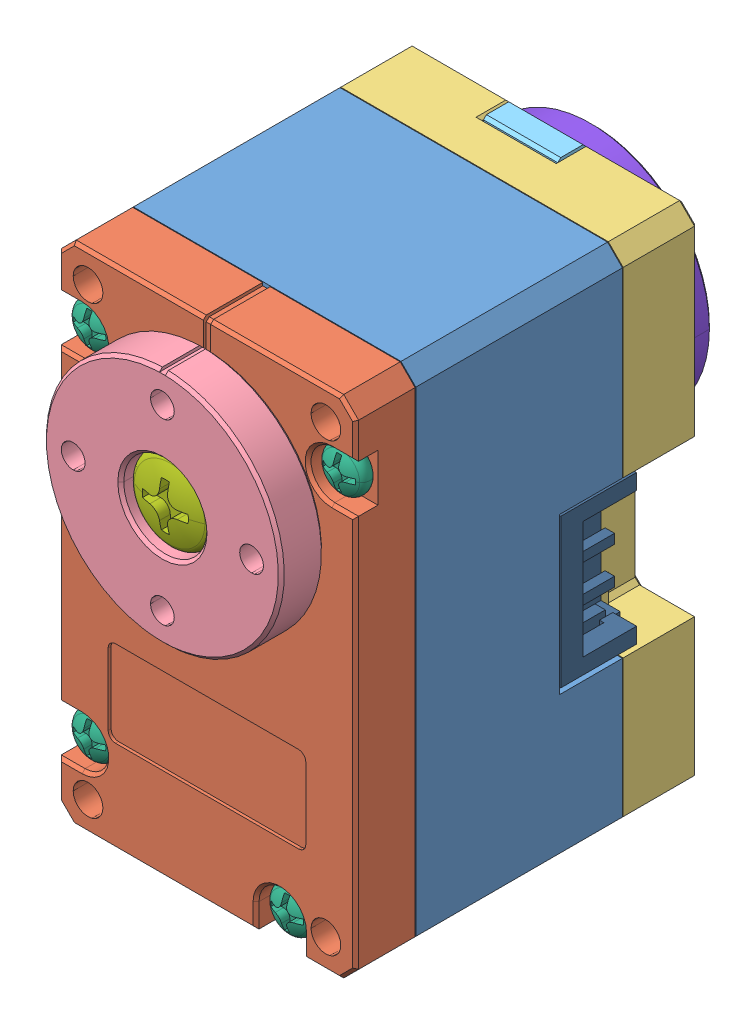
SolidWorks assembly XL-330, configuration Standard. Lengths in mm.
Overall size (20 34 29.02).
16 component instances, 10 part files, 0 mates.
Components (placement in the parent):
- XL-330.stp-1: XL-330.stp [Standard] at origin size (20 34 29.02)
  - DC15_A01_CASE_M_DUMMY.stp-1: DC15_A01_CASE_M_DUMMY.stp [Standard] at origin size (20 34 18.5)
  - DC15_A01_CASE_F_DUMMY.stp-1: DC15_A01_CASE_F_DUMMY.stp [Standard] at origin size (20 34 4)
  - DC15_A01_CASE_B_DUMMY.stp-1: DC15_A01_CASE_B_DUMMY.stp [Standard] at (0 0 -19.5) size (20 34 7.6)
  - DC15_A01_HORN_DUMMY.stp-1: DC15_A01_HORN_DUMMY.stp [Standard] at (0 0 3.6) x (-1 0 0) z (0 1 0) size (16 5.62 16.01)
  - DC15_A01_LED_CAP2_DUMMY.stp-1: DC15_A01_LED_CAP2_DUMMY.stp [Standard] at (0 7.5 -17.6) x (-1 0 0) z (0 0 -1) size (5 2 4.5)
  - PHS_1_7X20_5_DC10.stp-1: PHS_1_7X20_5_DC10.stp [Standard] at (8.4 4.5 2) x (-1 0 0) z (0 1 0) size (3 21.77 3)
  - PHS_1_7X20_5_DC10.stp-2: PHS_1_7X20_5_DC10.stp [Standard] at (-8.4 4.5 2) x (-1 0 0) z (0 1 0) size (3 21.77 3)
  - PHS_1_7X20_5_DC10.stp-3: PHS_1_7X20_5_DC10.stp [Standard] at (4.9 -22.9 2) x (-1 0 0) z (0 1 0) size (3 21.77 3)
  - PHS_1_7X20_5_DC10.stp-4: PHS_1_7X20_5_DC10.stp [Standard] at (-8.4 -19.4 2) x (-1 0 0) z (0 1 0) size (3 21.77 3)
  - BTS2_M2_6X8.stp-1: BTS2_M2_6X8.stp [Standard] at (0 0 4.9) x (-1 0 0) z (0 1 0) size (5.5 9.57 5.5)
  - DC15_A01_HORN_IDLE2_DUMMY.stp-1: DC15_A01_HORN_IDLE2_DUMMY.stp [Standard] at (0 0 -19.6) x (1 0 0) z (0 0 -1) size (16 16 4.15)
  - DC15_A01_IDLE_CAP_DUMMY.stp-1: DC15_A01_IDLE_CAP_DUMMY.stp [Standard] at (0 0 -22.3) x (1 0 0) z (0 1 0) size (6.8 4.6 6.8)
  - BTS2_M2_6X8.stp-2: BTS2_M2_6X8.stp [Standard] at (0 0 -20.7) x (1 0 0) z (0 1 0) size (5.5 9.57 5.5)
  - B3B-EH.stp-1: B3B-EH.stp [Standard] at (7.7 -9 -10.4) x (0 -1 0) z (1 0 0) size (10 9.2 3.8)
  - B3B-EH.stp-2: B3B-EH.stp [Standard] at (-7.7 -9 -10.4) x (0 1 0) z (-1 0 0) size (10 9.2 3.8)
